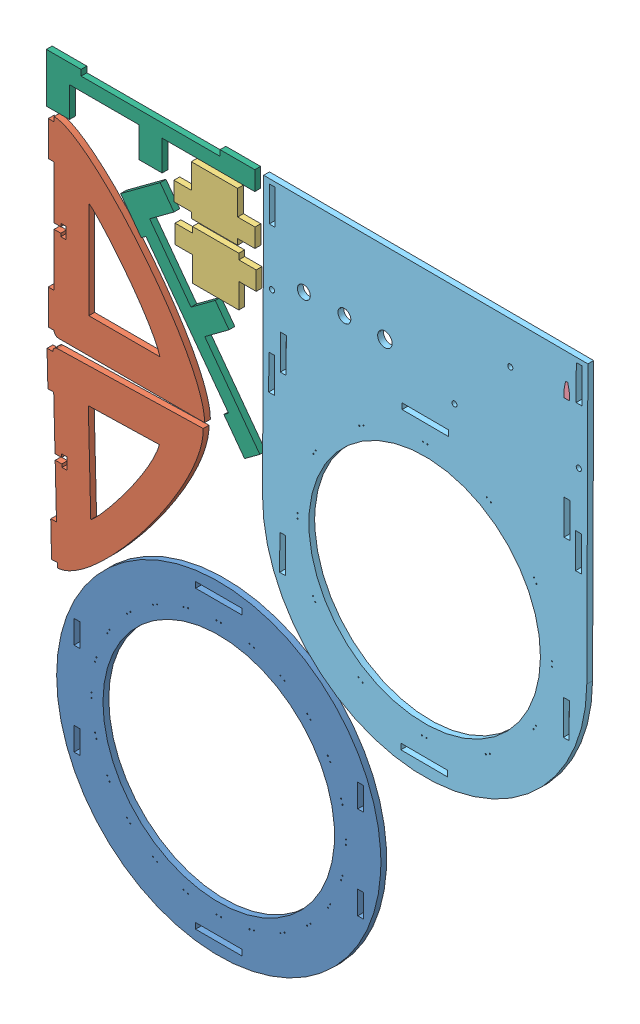
SolidWorks assembly arrangement, configuration Default. Lengths in mm.
Overall size (304.8 609.6 3.17).
9 component instances, 6 part files, 10 mates.
Components (placement in the parent):
- minute_ring-1: minute_ring [Default] at (-147.4578 9.5136 -3.175) size (177.8 177.8 3.17)
- support-1: support [Default] at (-238.5168 164.7378 0) x (0.999682 0.025212 0) z (0 0 -1) size (85.72 104.14 3.17)
- support-2: support [Default] at (-237.7655 169.9809 -3.175) size (85.72 104.14 3.17)
- top_spacer-1: top_spacer [Default] at (-137.1282 276.701 0) x (1 0 0) z (0 1 0) size (44.45 3.17 26.99)
- top_spacer-2: top_spacer [Default] at (-136.4634 246.4447 -3.175) x (1 0 0) z (0 -1 0) size (44.45 3.17 26.99)
- gnomon-1: gnomon [Default] at (44.9233 280.3776 -3.175) x (1 0 0) z (0 -1 0) size (3.17 3.17 8.26)
- faceplate-1: faceplate [Default] at (-34.552 150.9386 -3.175) x (-0.999992 0.003978 0) z (0 0 1) size (177.8 241.3 3.17)
- spacer_support-1: spacer_support [Default] at (-187.3965 242.3315 -3.175) x (0.803973 0.594666 0) z (0 0 1) size (26.99 114.3 3.17)
- spacer_support-2: spacer_support [Default] at (-222.9586 300.7056 0) x (0 -1 0) z (0 0 -1) size (26.99 114.3 3.17)
Mates (geometry in assembly coordinates):
- Coincident11: coincident aligned: plane of minute_ring-1 through (-147.4578 9.5136 0) normal (0 0 1); plane of support-2 through (-188.6846 233.136 0) normal (0 0 1)
- Coincident12: coincident aligned: plane of minute_ring-1 through (-147.4578 9.5136 0) normal (0 0 1); plane of support-1 through (-187.8593 102.8403 0) normal (0 0 1)
- Coincident13: coincident aligned: plane of minute_ring-1 through (-147.4578 9.5136 0) normal (0 0 1); plane of top_spacer-2 through (-136.4634 259.8432 0) normal (0 0 1)
- Coincident14: coincident aligned: plane of minute_ring-1 through (-147.4578 9.5136 0) normal (0 0 1); plane of top_spacer-1 through (-137.1282 263.3025 0) normal (0 0 1)
- Coincident15: coincident aligned: plane of minute_ring-1 through (-147.4578 9.5136 0) normal (0 0 1); plane of faceplate-1 through (-34.552 150.9386 0) normal (0 0 1)
- Coincident16: coincident aligned: plane of minute_ring-1 through (-147.4578 9.5136 0) normal (0 0 1); plane of spacer_support-2 through (-242.0086 276.8931 0) normal (0 0 1)
- Coincident17: coincident aligned: plane of minute_ring-1 through (-147.4578 9.5136 0) normal (0 0 1); plane of spacer_support-1 through (-179.5802 271.8077 0) normal (0 0 1)
- Coincident18: coincident aligned: plane of gnomon-1 through (41.7483 280.3776 0) normal (0 0 1); plane of minute_ring-1 through (-147.4578 9.5136 0) normal (0 0 1)
- Coincident19: coincident aligned: plane of minute_ring-1 through (-147.4578 9.5136 0) normal (0 0 1); plane of assembly through (0 0 0) normal (0 0 1)
- Parallel1: parallel aligned: line of spacer_support-2 through (-222.9586 300.7056 0) axis (1 0 0); line of assembly
